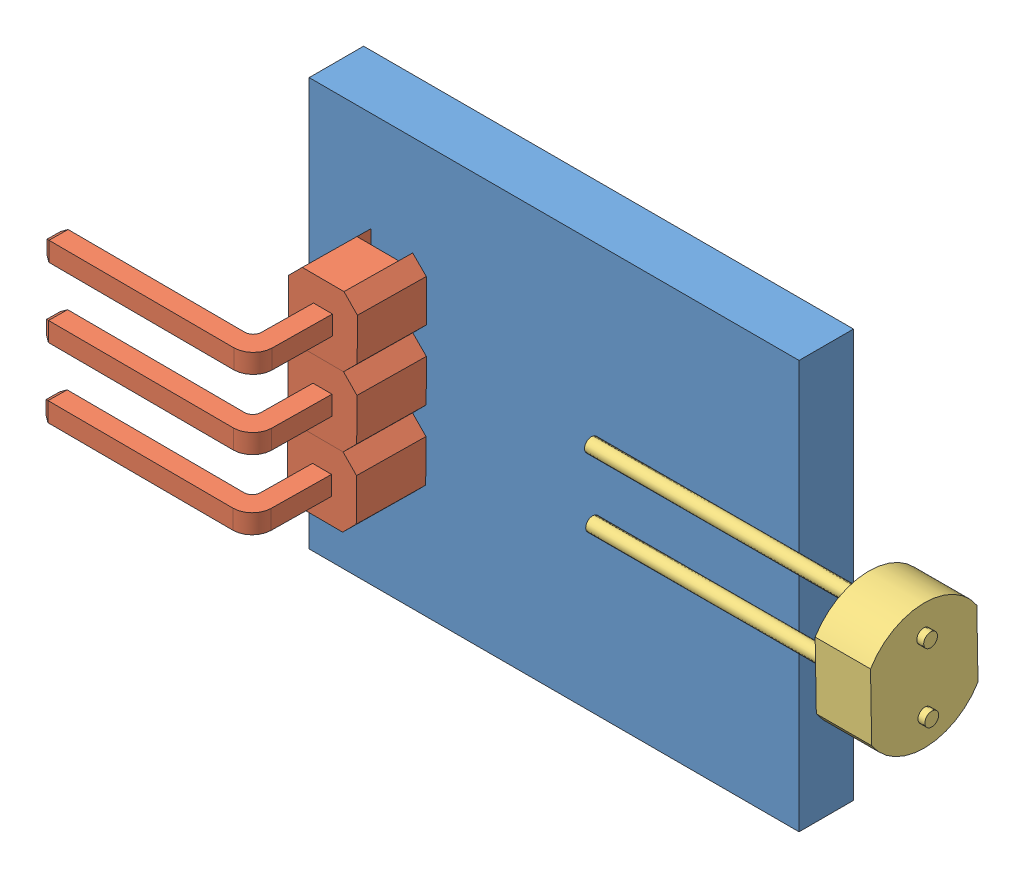
SolidWorks assembly KY-018, configuration Default. Lengths in mm.
Overall size (27.44 15 8.55).
4 component instances, 3 part files, 0 mates.
Components (placement in the parent):
- KY-018.stp-1: KY-018.stp [Default] at origin size (27.44 15 8.55)
  - board.stp-1: board.stp [Default] at (-16.037 -3.7963 -1) size (18 15 2)
  - User Library-PLS-3R.stp-1: User Library-PLS-3R.stp [Default] at (-13.0023 6.2551 0.9782) x (-0.999988 -0.001112 -0.004738) z (-0.001075 0.99997 -0.007711) size (8.62 8.45 7.62)
  - User Library-Photoresistor.stp-1: User Library-Photoresistor.stp [Default] at (6.8069 3.7234 1.2444) x (-0.001332 0.017452 -0.999847) z (0.000098 -0.999848 -0.017452) size (3.91 12.45 4.62)
